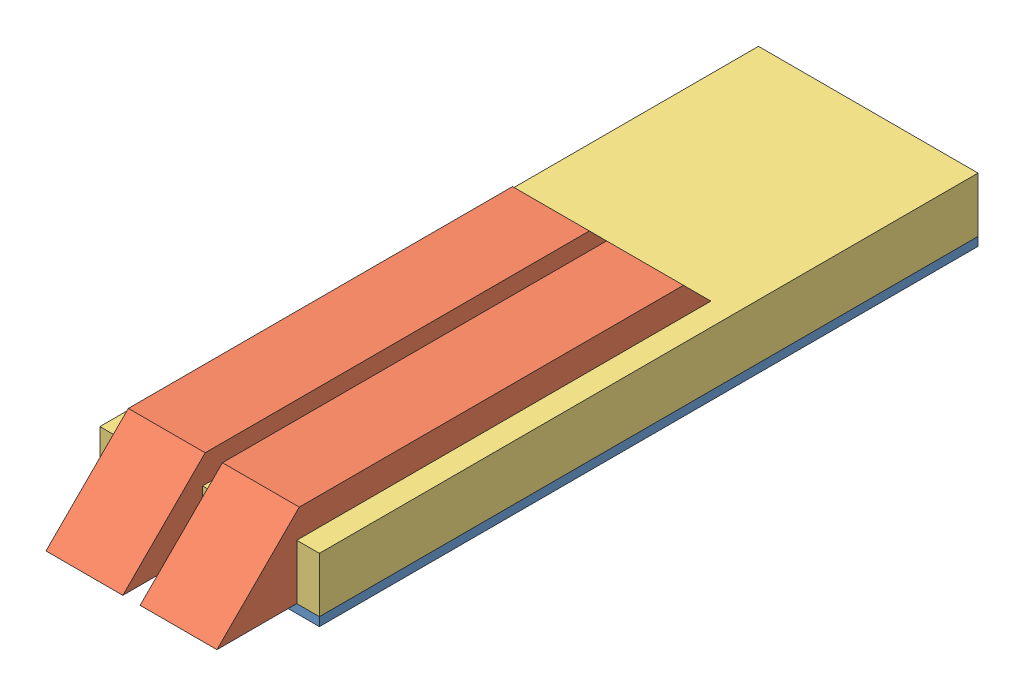
SolidWorks assembly Glass Slide with Electrode, configuration Default. Lengths in mm.
Overall size (25.4 10.53 85.43).
4 component instances, 3 part files, 7 mates.
Components (placement in the parent):
- Glass Slide-1: Glass Slide [Default] at (95.051 -11.2141 -11.4797) size (25.4 1 76.2)
- Aluminium Bars-1: Aluminium Bars [Default] at (98.0507 -10.2141 -2.2477) size (8.89 9.53 63.5)
- Aluminium Bars-2: Aluminium Bars [Default] at (108.9407 -10.2141 -2.2477) size (8.89 9.53 63.5)
- PDMS layer-1: PDMS layer [Default] at (95.051 -10.2141 -11.4797) size (25.4 6.35 76.2)
Mates (geometry in assembly coordinates):
- Coincident1: coincident anti-aligned: plane of Glass Slide-1 through (95.051 -10.2141 -11.4797) normal (0 1 0); plane of Aluminium Bars-2 through (108.9407 -10.2141 -2.2477) normal (0 -1 0)
- Coincident2: coincident anti-aligned: plane of Glass Slide-1 through (95.051 -10.2141 -11.4797) normal (0 1 0); plane of Aluminium Bars-1 through (98.0507 -10.2141 -2.2477) normal (0 -1 0)
- Coincident4: coincident aligned: line of Aluminium Bars-1 through (106.9407 -10.2141 -65.7477) axis (-1 0 0); line of Aluminium Bars-2 through (117.8307 -10.2141 -65.7477) axis (-1 0 0)
- Distance1: distance = 2 mm anti-aligned: plane of Aluminium Bars-1 through (106.9407 -0.6891 -2.2477) normal (1 0 0); plane of Aluminium Bars-2 through (108.9407 -0.6891 -2.2477) normal (-1 0 0)
- Coincident5: coincident: plane of Glass Slide-1 through (95.051 -10.2141 -11.4797) normal (0 1 0); plane of PDMS layer-1 through (95.051 -10.2141 -6.8402) normal (0 -1 0)
- Coincident6: coincident: plane of Glass Slide-1 through (120.451 -10.2141 -11.4797) normal (1 0 0); plane of PDMS layer-1 through (120.451 -3.8641 -11.4797) normal (1 0 0)
- Coincident7: coincident aligned: plane of Glass Slide-1 through (95.051 -10.2141 -87.6797) normal (0 0 -1); plane of PDMS layer-1 through (95.051 -3.8641 -87.6797) normal (0 0 -1)
